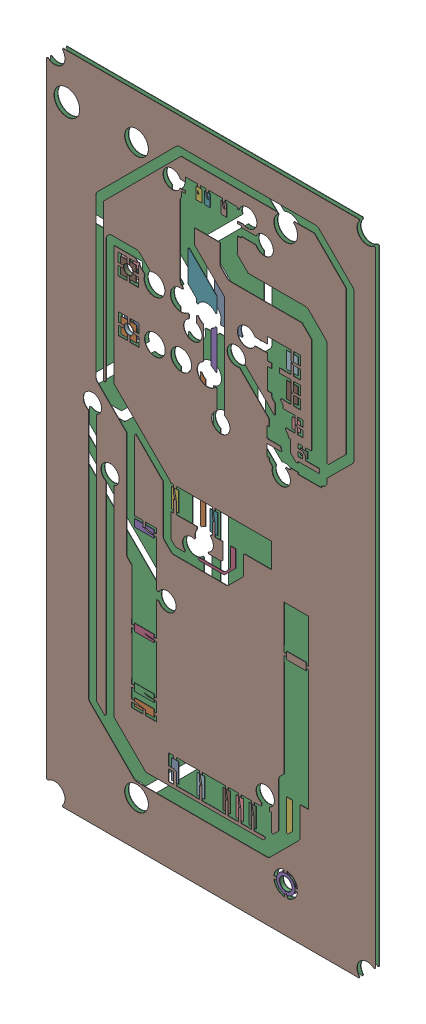
SolidWorks assembly GND, configuration Predeterminado. Lengths in mm.
Overall size (31.76 63.51 0.39).
96 component instances, 34 part files, 0 mates.
Components (placement in the parent):
- Polygon  (GND_L02_P001) on Bottom Layer-1: Polygon  (GND_L02_P001) on Bottom Layer [Predeterminado] at origin size (31.76 63.51 0.04)
  - Polygon Region (0 hole(s)) Bottom Layer-1: Polygon Region (0 hole(s)) Bottom Layer [Predeterminado] at (-68.317 -44.187 -0.4013) size (3.07 4.52 0.04)
    - Polygon Region (0 hole(s)) Bottom Layer-Part-1-1: Polygon Region (0 hole(s)) Bottom Layer-Part-1 [Predeterminado] at origin size (3.07 4.52 0.04)
  - Polygon Region (0 hole(s)) Bottom Layer-1-1: Polygon Region (0 hole(s)) Bottom Layer-1 [Predeterminado] at (-68.317 -44.187 -0.4013) size (0.5 12.94 0.04)
    - Polygon Region (0 hole(s)) Bottom Layer-Part-1-1-1: Polygon Region (0 hole(s)) Bottom Layer-Part-1-1 [Predeterminado] at origin size (0.5 12.94 0.04)
  - Polygon Region (16 hole(s)) Bottom Layer-1: Polygon Region (16 hole(s)) Bottom Layer [Predeterminado] at (-68.317 -44.187 -0.4013) size (31.76 63.51 0.04)
    - Polygon Region (16 hole(s)) Bottom Layer-Part-1-1: Polygon Region (16 hole(s)) Bottom Layer-Part-1 [Predeterminado] at origin size (31.76 63.51 0.04)
- Polygon  (GND_L01_P000) on Top Layer-1: Polygon  (GND_L01_P000) on Top Layer [Predeterminado] at origin size (31.76 63.51 0.04)
  - Polygon Region (0 hole(s)) Top Layer-1: Polygon Region (0 hole(s)) Top Layer [Predeterminado] at (-68.317 -44.187 -0.0457) size (3.6 2.72 0.04)
    - Polygon Region (0 hole(s)) Top Layer-Part-1-1: Polygon Region (0 hole(s)) Top Layer-Part-1 [Predeterminado] at origin size (3.6 2.72 0.04)
  - Polygon Region (0 hole(s)) Top Layer-1-1: Polygon Region (0 hole(s)) Top Layer-1 [Predeterminado] at (-68.317 -44.187 -0.0457) size (0.54 3.78 0.04)
    - Polygon Region (0 hole(s)) Top Layer-Part-1-1-1: Polygon Region (0 hole(s)) Top Layer-Part-1-1 [Predeterminado] at origin size (0.54 3.78 0.04)
  - Polygon Region (0 hole(s)) Top Layer-2-1: Polygon Region (0 hole(s)) Top Layer-2 [Predeterminado] at (-68.317 -44.187 -0.0457) size (0.56 3.06 0.04)
    - Polygon Region (0 hole(s)) Top Layer-Part-1-2-1: Polygon Region (0 hole(s)) Top Layer-Part-1-2 [Predeterminado] at origin size (0.56 3.06 0.04)
  - Polygon Region (0 hole(s)) Top Layer-3-1: Polygon Region (0 hole(s)) Top Layer-3 [Predeterminado] at (-68.317 -44.187 -0.0457) size (2.79 4.24 0.04)
    - Polygon Region (0 hole(s)) Top Layer-Part-1-3-1: Polygon Region (0 hole(s)) Top Layer-Part-1-3 [Predeterminado] at origin size (2.79 4.24 0.04)
  - Polygon Region (38 hole(s)) Top Layer-1: Polygon Region (38 hole(s)) Top Layer [Predeterminado] at (-68.317 -44.187 -0.0457) size (31.76 63.51 0.04)
    - Polygon Region (38 hole(s)) Top Layer-Part-1-1: Polygon Region (38 hole(s)) Top Layer-Part-1 [Predeterminado] at origin size (31.76 63.51 0.04)
- Pad SWD-1(12.954mm,48.387mm) on Multi-Layer-1: Pad SWD-1(12.954mm,48.387mm) on Multi-Layer [Predeterminado] at origin size (1.5 1.5 0.39)
  - Pad Hole-1-1: Pad Hole-1 [Predeterminado] at (12.954 48.387 -0.4013) size (0.95 0.95 0.39)
    - Pad Hole-Part-1-1-1: Pad Hole-Part-1-1 [Predeterminado] at origin size (0.95 0.95 0.39)
  - Pad Copper-1: Pad Copper [Predeterminado] at (-68.317 -44.187 -0.4013) size (1.5 1.5 0.04)
    - Pad Copper-Part-1-1: Pad Copper-Part-1 [Predeterminado] at origin size (1.5 1.5 0.04)
  - Pad Copper-1-1: Pad Copper-1 [Predeterminado] at (-68.317 -44.187 -0.0457) size (1.5 1.5 0.04)
    - Pad Copper-Part-1-1-1: Pad Copper-Part-1-1 [Predeterminado] at origin size (1.5 1.5 0.04)
- Pad UART-1(13mm,43.4mm) on Multi-Layer-1: Pad UART-1(13mm,43.4mm) on Multi-Layer [Predeterminado] at origin size (1.5 1.5 0.39)
  - Pad Hole-1-1: Pad Hole-1 [Predeterminado] at (13 43.4 -0.4013) size (0.95 0.95 0.39)
    - Pad Hole-Part-1-1-1: Pad Hole-Part-1-1 [Predeterminado] at origin size (0.95 0.95 0.39)
  - Pad Copper-2-1: Pad Copper-2 [Predeterminado] at (-68.317 -44.187 -0.4013) size (1.5 1.5 0.04)
    - Pad Copper-Part-1-2-1: Pad Copper-Part-1-2 [Predeterminado] at origin size (1.5 1.5 0.04)
  - Pad Copper-3-1: Pad Copper-3 [Predeterminado] at (-68.317 -44.187 -0.0457) size (1.5 1.5 0.04)
    - Pad Copper-Part-1-3-1: Pad Copper-Part-1-3 [Predeterminado] at origin size (1.5 1.5 0.04)
- Pad U1-3(28.178mm,4.578mm) on Multi-Layer-1: Pad U1-3(28.178mm,4.578mm) on Multi-Layer [Predeterminado] at origin size (1.79 1.79 0.39)
  - Pad Hole-1: Pad Hole [Predeterminado] at (28.1784 4.5777 -0.4013) size (1.24 1.24 0.39)
    - Pad Hole-Part-1-1: Pad Hole-Part-1 [Predeterminado] at origin size (1.24 1.24 0.39)
  - Top Layer-1: Top Layer [Predeterminado] at (28.1784 4.5777 -0.4013) size (1.79 1.79 0.04)
    - Top Layer-Part-1-1: Top Layer-Part-1 [Predeterminado] at origin size (1.79 1.79 0.04)
  - Top Layer-2: Top Layer [Predeterminado] at (28.1784 4.5777 -0.0457) size (1.79 1.79 0.04)
    - Top Layer-Part-1-1: Top Layer-Part-1 [Predeterminado] at origin size (1.79 1.79 0.04)
- Pad RAK4600-42(17.475mm,31.391mm) on Top Layer-1: Pad RAK4600-42(17.475mm,31.391mm) on Top Layer [Predeterminado] at origin size (0.7 1.9 0.04)
  - Pad RAK4600-42(17.475mm,31.391mm) on Top Layer-1-1: Pad RAK4600-42(17.475mm,31.391mm) on Top Layer-1 [Predeterminado] at (-68.317 -44.187 -0.0457) size (0.7 1.9 0.04)
    - Pad RAK4600-42(17.475mm,31.391mm) on Top Layer-Part-1-1: Pad RAK4600-42(17.475mm,31.391mm) on Top Layer-Part-1 [Predeterminado] at origin size (0.7 1.9 0.04)
- Pad RAK4600-39(21.225mm,31.391mm) on Top Layer-1: Pad RAK4600-39(21.225mm,31.391mm) on Top Layer [Predeterminado] at origin size (0.7 1.9 0.04)
  - Pad RAK4600-39(21.225mm,31.391mm) on Top Layer-1-1: Pad RAK4600-39(21.225mm,31.391mm) on Top Layer-1 [Predeterminado] at (-68.317 -44.187 -0.0457) size (0.7 1.9 0.04)
    - Pad RAK4600-39(21.225mm,31.391mm) on Top Layer-Part-1-1: Pad RAK4600-39(21.225mm,31.391mm) on Top Layer-Part-1 [Predeterminado] at origin size (0.7 1.9 0.04)
- Pad RAK4600-31(29.2mm,23.75mm) on Top Layer-1: Pad RAK4600-31(29.2mm,23.75mm) on Top Layer [Predeterminado] at origin size (1.9 0.7 0.04)
  - Pad RAK4600-31(29.2mm,23.75mm) on Top Layer-1-1: Pad RAK4600-31(29.2mm,23.75mm) on Top Layer-1 [Predeterminado] at (-68.317 -44.187 -0.0457) size (1.9 0.7 0.04)
    - Pad RAK4600-31(29.2mm,23.75mm) on Top Layer-Part-1-1: Pad RAK4600-31(29.2mm,23.75mm) on Top Layer-Part-1 [Predeterminado] at origin size (1.9 0.7 0.04)
- Pad RAK4600-20(24.975mm,8.691mm) on Top Layer-1: Pad RAK4600-20(24.975mm,8.691mm) on Top Layer [Predeterminado] at origin size (0.7 1.9 0.04)
  - Pad RAK4600-20(24.975mm,8.691mm) on Top Layer-1-1: Pad RAK4600-20(24.975mm,8.691mm) on Top Layer-1 [Predeterminado] at (-68.317 -44.187 -0.0457) size (0.7 1.9 0.04)
    - Pad RAK4600-20(24.975mm,8.691mm) on Top Layer-Part-1-1: Pad RAK4600-20(24.975mm,8.691mm) on Top Layer-Part-1 [Predeterminado] at origin size (0.7 1.9 0.04)
- Pad RAK4600-19(23.725mm,8.691mm) on Top Layer-1: Pad RAK4600-19(23.725mm,8.691mm) on Top Layer [Predeterminado] at origin size (0.7 1.9 0.04)
  - Pad RAK4600-19(23.725mm,8.691mm) on Top Layer-1-1: Pad RAK4600-19(23.725mm,8.691mm) on Top Layer-1 [Predeterminado] at (-68.317 -44.187 -0.0457) size (0.7 1.9 0.04)
    - Pad RAK4600-19(23.725mm,8.691mm) on Top Layer-Part-1-1: Pad RAK4600-19(23.725mm,8.691mm) on Top Layer-Part-1 [Predeterminado] at origin size (0.7 1.9 0.04)
- Pad RAK4600-18(22.475mm,8.691mm) on Top Layer-1: Pad RAK4600-18(22.475mm,8.691mm) on Top Layer [Predeterminado] at origin size (0.7 1.9 0.04)
  - Pad RAK4600-18(22.475mm,8.691mm) on Top Layer-1-1: Pad RAK4600-18(22.475mm,8.691mm) on Top Layer-1 [Predeterminado] at (-68.317 -44.187 -0.0457) size (0.7 1.9 0.04)
    - Pad RAK4600-18(22.475mm,8.691mm) on Top Layer-Part-1-1: Pad RAK4600-18(22.475mm,8.691mm) on Top Layer-Part-1 [Predeterminado] at origin size (0.7 1.9 0.04)
- Pad RAK4600-16(19.975mm,8.691mm) on Top Layer-1: Pad RAK4600-16(19.975mm,8.691mm) on Top Layer [Predeterminado] at origin size (0.7 1.9 0.04)
  - Pad RAK4600-16(19.975mm,8.691mm) on Top Layer-1-1: Pad RAK4600-16(19.975mm,8.691mm) on Top Layer-1 [Predeterminado] at (-68.317 -44.187 -0.0457) size (0.7 1.9 0.04)
    - Pad RAK4600-16(19.975mm,8.691mm) on Top Layer-Part-1-1: Pad RAK4600-16(19.975mm,8.691mm) on Top Layer-Part-1 [Predeterminado] at origin size (0.7 1.9 0.04)
- Pad RAK4600-14(17.475mm,8.691mm) on Top Layer-1: Pad RAK4600-14(17.475mm,8.691mm) on Top Layer [Predeterminado] at origin size (0.7 1.9 0.04)
  - Pad RAK4600-14(17.475mm,8.691mm) on Top Layer-1-1: Pad RAK4600-14(17.475mm,8.691mm) on Top Layer-1 [Predeterminado] at (-68.317 -44.187 -0.0457) size (0.7 1.9 0.04)
    - Pad RAK4600-14(17.475mm,8.691mm) on Top Layer-Part-1-1: Pad RAK4600-14(17.475mm,8.691mm) on Top Layer-Part-1 [Predeterminado] at origin size (0.7 1.9 0.04)
- Pad RAK4600-13(14.5mm,12.5mm) on Top Layer-1: Pad RAK4600-13(14.5mm,12.5mm) on Top Layer [Predeterminado] at origin size (1.9 0.7 0.04)
  - Pad RAK4600-13(14.5mm,12.5mm) on Top Layer-1-1: Pad RAK4600-13(14.5mm,12.5mm) on Top Layer-1 [Predeterminado] at (-68.317 -44.187 -0.0457) size (1.9 0.7 0.04)
    - Pad RAK4600-13(14.5mm,12.5mm) on Top Layer-Part-1-1: Pad RAK4600-13(14.5mm,12.5mm) on Top Layer-Part-1 [Predeterminado] at origin size (1.9 0.7 0.04)
- Pad RAK4600-12(14.5mm,13.75mm) on Top Layer-1: Pad RAK4600-12(14.5mm,13.75mm) on Top Layer [Predeterminado] at origin size (1.9 0.7 0.04)
  - Pad RAK4600-12(14.5mm,13.75mm) on Top Layer-1-1: Pad RAK4600-12(14.5mm,13.75mm) on Top Layer-1 [Predeterminado] at (-68.317 -44.187 -0.0457) size (1.9 0.7 0.04)
    - Pad RAK4600-12(14.5mm,13.75mm) on Top Layer-Part-1-1: Pad RAK4600-12(14.5mm,13.75mm) on Top Layer-Part-1 [Predeterminado] at origin size (1.9 0.7 0.04)
- Pad RAK4600-8(14.5mm,18.75mm) on Top Layer-1: Pad RAK4600-8(14.5mm,18.75mm) on Top Layer [Predeterminado] at origin size (1.9 0.7 0.04)
  - Pad RAK4600-8(14.5mm,18.75mm) on Top Layer-1-1: Pad RAK4600-8(14.5mm,18.75mm) on Top Layer-1 [Predeterminado] at (-68.317 -44.187 -0.0457) size (1.9 0.7 0.04)
    - Pad RAK4600-8(14.5mm,18.75mm) on Top Layer-Part-1-1: Pad RAK4600-8(14.5mm,18.75mm) on Top Layer-Part-1 [Predeterminado] at origin size (1.9 0.7 0.04)
- Pad RAK4600-1(14.5mm,27.5mm) on Top Layer-1: Pad RAK4600-1(14.5mm,27.5mm) on Top Layer [Predeterminado] at origin size (1.9 0.7 0.04)
  - Pad RAK4600-1(14.5mm,27.5mm) on Top Layer-1-1: Pad RAK4600-1(14.5mm,27.5mm) on Top Layer-1 [Predeterminado] at (-68.317 -44.187 -0.0457) size (1.9 0.7 0.04)
    - Pad RAK4600-1(14.5mm,27.5mm) on Top Layer-Part-1-1: Pad RAK4600-1(14.5mm,27.5mm) on Top Layer-Part-1 [Predeterminado] at origin size (1.9 0.7 0.04)
- Pad ADXL345-5(19.8mm,58.097mm) on Top Layer-1: Pad ADXL345-5(19.8mm,58.097mm) on Top Layer [Predeterminado] at origin size (0.55 1.15 0.04)
  - Pad ADXL345-5(19.8mm,58.097mm) on Top Layer-1-1: Pad ADXL345-5(19.8mm,58.097mm) on Top Layer-1 [Predeterminado] at (-68.317 -44.187 -0.0457) size (0.55 1.15 0.04)
    - Pad ADXL345-5(19.8mm,58.097mm) on Top Layer-Part-1-1: Pad ADXL345-5(19.8mm,58.097mm) on Top Layer-Part-1 [Predeterminado] at origin size (0.55 1.15 0.04)
- Pad ADXL345-4(20.6mm,58.097mm) on Top Layer-1: Pad ADXL345-4(20.6mm,58.097mm) on Top Layer [Predeterminado] at origin size (0.55 1.15 0.04)
  - Pad ADXL345-4(20.6mm,58.097mm) on Top Layer-1-1: Pad ADXL345-4(20.6mm,58.097mm) on Top Layer-1 [Predeterminado] at (-68.317 -44.187 -0.0457) size (0.55 1.15 0.04)
    - Pad ADXL345-4(20.6mm,58.097mm) on Top Layer-Part-1-1: Pad ADXL345-4(20.6mm,58.097mm) on Top Layer-Part-1 [Predeterminado] at origin size (0.55 1.15 0.04)
- Pad ADXL345-2(22.2mm,58.097mm) on Top Layer-1: Pad ADXL345-2(22.2mm,58.097mm) on Top Layer [Predeterminado] at origin size (0.55 1.15 0.04)
  - Pad ADXL345-2(22.2mm,58.097mm) on Top Layer-1-1: Pad ADXL345-2(22.2mm,58.097mm) on Top Layer-1 [Predeterminado] at (-68.317 -44.187 -0.0457) size (0.55 1.15 0.04)
    - Pad ADXL345-2(22.2mm,58.097mm) on Top Layer-Part-1-1: Pad ADXL345-2(22.2mm,58.097mm) on Top Layer-Part-1 [Predeterminado] at origin size (0.55 1.15 0.04)
- Pad R3-1(29.95mm,41.5mm) on Top Layer-1: Pad R3-1(29.95mm,41.5mm) on Top Layer [Predeterminado] at origin size (0.7 0.6 0.04)
  - Pad R3-1(29.95mm,41.5mm) on Top Layer-1-1: Pad R3-1(29.95mm,41.5mm) on Top Layer-1 [Predeterminado] at (-68.317 -44.187 -0.0457) size (0.7 0.6 0.04)
    - Pad R3-1(29.95mm,41.5mm) on Top Layer-Part-1-1: Pad R3-1(29.95mm,41.5mm) on Top Layer-Part-1 [Predeterminado] at origin size (0.7 0.6 0.04)
- Pad C2-1(29.2mm,43.5mm) on Top Layer-1: Pad C2-1(29.2mm,43.5mm) on Top Layer [Predeterminado] at origin size (0.78 0.99 0.04)
  - Pad C2-1(29.2mm,43.5mm) on Top Layer-1-1: Pad C2-1(29.2mm,43.5mm) on Top Layer-1 [Predeterminado] at (-68.317 -44.187 -0.0457) size (0.78 0.99 0.04)
    - Pad C2-1(29.2mm,43.5mm) on Top Layer-Part-1-1: Pad C2-1(29.2mm,43.5mm) on Top Layer-Part-1 [Predeterminado] at origin size (0.78 0.99 0.04)
- Pad C1-1(28.81mm,46mm) on Top Layer-1: Pad C1-1(28.81mm,46mm) on Top Layer [Predeterminado] at origin size (1.1 1.57 0.04)
  - Pad C1-1(28.81mm,46mm) on Top Layer-1-1: Pad C1-1(28.81mm,46mm) on Top Layer-1 [Predeterminado] at (-68.317 -44.187 -0.0457) size (1.1 1.57 0.04)
    - Pad C1-1(28.81mm,46mm) on Top Layer-Part-1-1: Pad C1-1(28.81mm,46mm) on Top Layer-Part-1 [Predeterminado] at origin size (1.1 1.57 0.04)
- Pad C3-1(28.81mm,48.5mm) on Top Layer-1: Pad C3-1(28.81mm,48.5mm) on Top Layer [Predeterminado] at origin size (1.1 1.57 0.04)
  - Pad C3-1(28.81mm,48.5mm) on Top Layer-1-1: Pad C3-1(28.81mm,48.5mm) on Top Layer-1 [Predeterminado] at (-68.317 -44.187 -0.0457) size (1.1 1.57 0.04)
    - Pad C3-1(28.81mm,48.5mm) on Top Layer-Part-1-1: Pad C3-1(28.81mm,48.5mm) on Top Layer-Part-1 [Predeterminado] at origin size (1.1 1.57 0.04)
